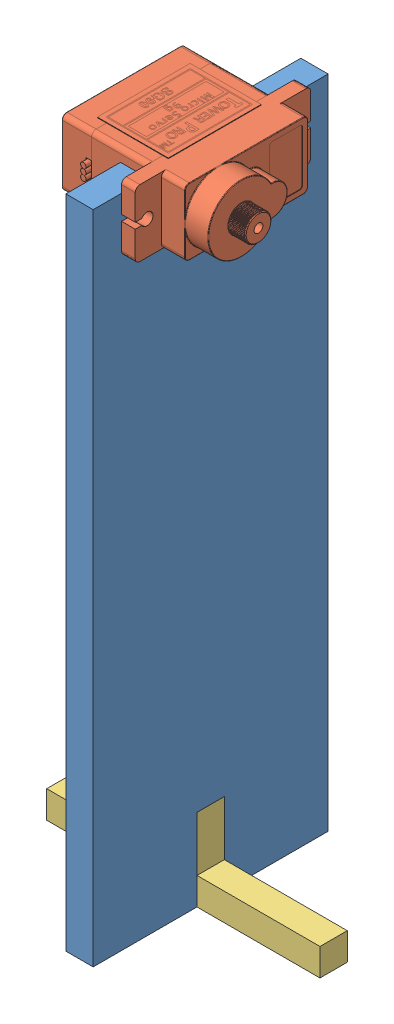
SolidWorks assembly Assem2, configuration Default. Lengths in mm.
Overall size (50 122.3 43).
3 component instances, 3 part files, 6 mates.
Components (placement in the parent):
- stand-1: stand [Default] at (15.8951 8.8359 80.3187) size (5 120 43)
- SG90 - Micro Servo 9g - Tower Pro.1-1: SG90 - Micro Servo 9g - Tower Pro.1 [Peça] at (15.7451 124.9359 102.0687) x (0 0 -1) z (0 -1 0) size (32.1 29.95 12.4)
- base-1: base [Default] at (43.3951 8.8359 99.3187) x (0 0 1) z (-1 0 0) size (5 15 50)
Mates (geometry in assembly coordinates):
- Coincident1: coincident: plane of assembly; plane of assembly; plane of stand-1 through (20.8951 128.8359 113.3187) normal (0 0 -1); plane of SG90 - Micro Servo 9g - Tower Pro.1-1 through (20.8951 119.6859 113.3187) normal (0 0 1)
- Coincident3: coincident: plane of assembly; plane of assembly; plane of stand-1 through (20.8951 118.8359 113.3187) normal (0 1 0); plane of SG90 - Micro Servo 9g - Tower Pro.1-1 through (23.3951 118.8359 117.2687) normal (0 -1 0)
- Coincident4: coincident: plane of assembly; plane of assembly; plane of stand-1 through (20.8951 8.8359 80.3187) normal (1 0 0); plane of SG90 - Micro Servo 9g - Tower Pro.1-1 through (20.8951 119.6859 117.2687) normal (-1 0 0)
- Coincident5: coincident: plane of assembly; plane of assembly; plane of stand-1 through (20.8951 8.8359 104.3187) normal (0 0 -1); plane of base-1 through (43.3951 8.8359 104.3187) normal (0 0 1)
- Coincident6: coincident: plane of assembly; plane of assembly; plane of stand-1 through (20.8951 8.8359 80.3187) normal (1 0 0); plane of base-1 through (20.8951 23.8359 104.3187) normal (1 0 0)
- Coincident7: coincident: plane of assembly; plane of assembly; plane of stand-1 through (20.8951 8.8359 80.3187) normal (0 -1 0); plane of base-1 through (43.3951 8.8359 104.3187) normal (0 -1 0)
